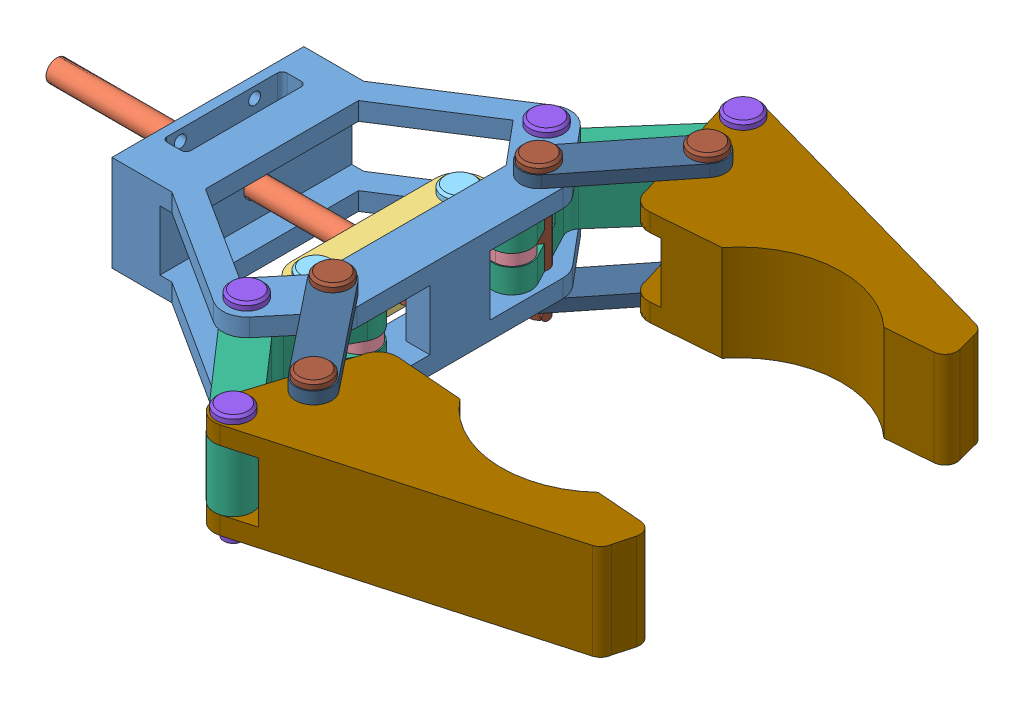
SolidWorks assembly end effactor assem, configuration Default. Lengths in mm.
Overall size (309.65 58.05 248.35).
25 component instances, 11 part files, 58 mates.
Components (placement in the parent):
- part1-2: part1 [Default] at origin size (105.05 40.02 145)
- part10-3: part10 [Default] at (74.5 20 0) x (-1 0 0) z (0 0.889527 -0.456883) size (150 23 23)
- part2-3: part2 [Default] at (62.5 20 0) x (0 0 -1) z (0 -1 0) size (80 20 20)
- part33-1: part33 [Default] at (62.5 20 -30) x (0.995937 0 -0.090048) z (0 -1 0) size (35 15 5)
- part33-2: part33 [Default] at (62.5 20 30) x (0.995937 0 0.090048) z (0 -1 0) size (35 15 5)
- part6-3: part6 [Default] at (62.5 5.25 30) x (1 0 -0.000264) z (0.000264 0 1) size (14 27.8 14)
- part6-4: part6 [Default] at (62.5 5.25 -30) size (14 27.8 14)
- part4-3: part4 [Default] at (66.2 7.5 62.5) x (-0.46713 0 0.884189) z (-0.884189 0 -0.46713) size (71.61 25 70.24)
- part4-4: part4 [Default] at (66.2 32.5 -62.5) x (-0.46713 0 -0.884189) z (-0.884189 0 0.46713) size (71.61 25 70.24)
- part8-3: part8 [Default] at (82.4187 2.5 -31.801) size (14 33.05 14)
- part8-4: part8 [Default] at (82.4187 2.5 31.801) size (14 33.05 14)
- part9-3: part9 [Default] at (104.4001 -5 -106.3078) x (-0.280054 0 -0.959984) z (0.959984 0 -0.280054) size (14 48.05 14)
- part9-4: part9 [Default] at (104.4001 -5 106.3078) x (-0.352892 0 -0.935664) z (0.935664 0 -0.352892) size (14 48.05 14)
- part9-5: part9 [Default] at (66.2 -4.98 -62.5) size (14 48.05 14)
- part9-6: part9 [Default] at (66.2 -4.98 62.5) size (14 48.05 14)
- part5-3: part5 [Default] at (109.3462 20 94.447) x (0.996905 0 0.07861) z (0.07861 0 -0.996905) size (133.83 40 62.87)
- part5-4: part5 [Default] at (109.3462 20 -94.447) x (0.996905 0 -0.07861) z (0.07861 0 0.996905) size (133.83 40 62.87)
- Part3-5: Part3 [Default] at (98.1062 42.52 62.5205) x (0.622248 0 0.78282) z (0 1 0) size (65 15 5)
- Part3-6: Part3 [Default] at (98.1062 -2.5 -62.5205) x (0.622248 0 -0.78282) z (0 -1 0) size (65 15 5)
- Part3-8: Part3 [Default] at (98.1062 42.52 -62.5205) x (0.622248 0 -0.78282) z (0 1 0) size (65 15 5)
- Part3-9: Part3 [Default] at (98.1062 -2.5 62.5205) x (0.622248 0 0.78282) z (0 -1 0) size (65 15 5)
- part7-3: part7 [Default] at (82.55 -9.98 -42.95) x (0.296614 0 -0.954998) z (0.954998 0 0.296614) size (14 58.05 14)
- part7-4: part7 [Default] at (82.55 -9.98 42.95) size (14 58.05 14)
- part7-5: part7 [Default] at (113.6624 -9.98 -82.091) size (14 58.05 14)
- part7-6: part7 [Default] at (113.6624 -9.98 82.091) size (14 58.05 14)
Mates (geometry in assembly coordinates):
- Concentric2: concentric anti-aligned: cylinder of part1-2 through (92.5 20 0) axis (-1 0 0) radius 5; cylinder of part10-3 through (42.8764 20 0) axis (1 0 0) radius 4.5
- LimitDistance1: limit distance = 0 mm anti-aligned: plane of part10-3 through (-9.5 15.9971 2.056) normal (1 0 0); plane of part1-2 through (-9.5 20 0) normal (-1 0 0)
- Concentric4: concentric aligned: cylinder of part10-3 through (42.8764 20 0) axis (1 0 0) radius 4.5; cylinder of part2-3 through (20.8764 20 0) axis (1 0 0) radius 5
- Coincident1: coincident anti-aligned: plane of part10-3 through (38.8764 11.0085 0.3917) normal (-1 0 0); plane of part2-3 through (38.8764 20 0) normal (1 0 0)
- Parallel1: parallel anti-aligned: plane of part2-3 through (30.8764 20 0) normal (0 -1 0); plane of assembly through (0 0 0) normal (0 1 0)
- Concentric5: concentric anti-aligned: cylinder of part2-3 through (30.8764 30 -30) axis (0 -1 0) radius 4; cylinder of part33-1 through (30.8764 17.5 -30) axis (0 1 0) radius 4
- Concentric6: concentric anti-aligned: cylinder of part2-3 through (30.8764 30 30) axis (0 -1 0) radius 4; cylinder of part33-2 through (30.8764 17.5 30) axis (0 1 0) radius 4
- Coincident3: coincident anti-aligned: plane of part2-3 through (20.8764 22.5 -40) normal (0 -1 0); plane of part33-1 through (30.8764 22.5 -30) normal (0 1 0)
- Coincident4: coincident anti-aligned: plane of part2-3 through (20.8764 22.5 40) normal (0 -1 0); plane of part33-2 through (30.8764 22.5 30) normal (0 1 0)
- Concentric7: concentric aligned: cylinder of part2-3 through (30.8764 30 30) axis (0 -1 0) radius 4; cylinder of part6-3 through (30.8764 5.25 30) axis (0 -1 0) radius 4
- Coincident5: coincident anti-aligned: plane of part2-3 through (30.8764 30 30) normal (0 1 0); plane of part6-3 through (30.8764 30 30) normal (0 -1 0)
- Concentric8: concentric aligned: cylinder of part2-3 through (30.8764 30 -30) axis (0 -1 0) radius 4; cylinder of part6-4 through (30.8764 5.25 -30) axis (0 -1 0) radius 4
- Coincident6: coincident anti-aligned: plane of part2-3 through (30.8764 30 30) normal (0 1 0); plane of part6-4 through (30.8764 30 -30) normal (0 -1 0)
- Concentric9: concentric anti-aligned: cylinder of part33-2 through (50.8296 17.5 31.3676) axis (0 1 0) radius 4; cylinder of part4-3 through (50.8296 32.5 31.3676) axis (0 -1 0) radius 4
- Coincident7: coincident anti-aligned: plane of part33-2 through (30.8764 22.5 30) normal (0 1 0); plane of part4-3 through (103.0968 22.5 -3.3593) normal (0 -1 0)
- Concentric10: concentric anti-aligned: cylinder of part1-2 through (66.2 32.52 62.5) axis (0 1 0) radius 4; cylinder of part4-3 through (66.2 32.5 62.5) axis (0 -1 0) radius 4
- Concentric13: concentric aligned: cylinder of part33-1 through (50.8296 17.5 -31.3676) axis (0 1 0) radius 4; cylinder of part4-4 through (50.8296 7.5 -31.3676) axis (0 1 0) radius 4
- Concentric14: concentric aligned: cylinder of part1-2 through (66.2 32.52 -62.5) axis (0 1 0) radius 4; cylinder of part4-4 through (66.2 7.5 -62.5) axis (0 1 0) radius 4
- Coincident8: coincident anti-aligned: plane of part33-1 through (30.8764 22.5 -30) normal (0 1 0); plane of part4-4 through (103.0968 22.5 3.3593) normal (0 -1 0)
- Concentric15: concentric anti-aligned: cylinder of part4-4 through (50.8296 7.5 -31.3676) axis (0 1 0) radius 4; cylinder of part8-3 through (50.8296 2.5 -31.3676) axis (0 -1 0) radius 4
- Concentric16: concentric anti-aligned: cylinder of part4-4 through (50.8296 7.5 -31.3676) axis (0 1 0) radius 4; cylinder of part8-3 through (50.8296 2.5 -31.3676) axis (0 -1 0) radius 4
- Coincident10: coincident anti-aligned: plane of part4-4 through (66.2 32.5 -62.5) normal (0 1 0); plane of part8-3 through (50.8296 32.5 -31.3676) normal (0 -1 0)
- Concentric17: concentric aligned: cylinder of part4-3 through (50.8296 32.5 31.3676) axis (0 -1 0) radius 4; cylinder of part8-4 through (50.8296 2.5 31.3676) axis (0 -1 0) radius 4
- Coincident11: coincident anti-aligned: plane of part4-3 through (66.2 32.5 62.5) normal (0 1 0); plane of part8-4 through (50.8296 32.5 31.3676) normal (0 -1 0)
- Concentric18: concentric anti-aligned: cylinder of part1-2 through (66.2 32.52 62.5) axis (0 1 0) radius 4; cylinder of part9-6 through (66.2 -4.98 62.5) axis (0 -1 0) radius 4
- Concentric19: concentric anti-aligned: cylinder of part1-2 through (66.2 32.52 -62.5) axis (0 1 0) radius 4; cylinder of part9-5 through (66.2 -4.98 -62.5) axis (0 -1 0) radius 4
- Coincident12: coincident anti-aligned: plane of part1-2 through (0 40.02 0) normal (0 1 0); plane of part9-6 through (66.2 40.02 62.5) normal (0 -1 0)
- Coincident13: coincident anti-aligned: plane of part1-2 through (0 40.02 0) normal (0 1 0); plane of part9-5 through (66.2 40.02 -62.5) normal (0 -1 0)
- Concentric21: concentric anti-aligned: cylinder of part4-4 through (124.0834 7.5 -57.2196) axis (0 1 0) radius 4; cylinder of part5-4 through (124.0834 40 -57.2196) axis (0 -1 0) radius 4
- Coincident14: coincident anti-aligned: plane of part4-4 through (66.2 32.5 -62.5) normal (0 1 0); plane of part5-4 through (116.0834 32.5 -65.2196) normal (0 -1 0)
- Concentric22: concentric anti-aligned: cylinder of part4-3 through (124.0834 32.5 57.2196) axis (0 -1 0) radius 4; cylinder of part5-3 through (124.0834 0 57.2196) axis (0 1 0) radius 4
- Coincident15: coincident anti-aligned: plane of part4-3 through (66.2 32.5 62.5) normal (0 1 0); plane of part5-3 through (116.0834 32.5 65.2196) normal (0 -1 0)
- Concentric23: concentric anti-aligned: cylinder of part9-4 through (124.0834 -5 57.2196) axis (0 -1 0) radius 4; cylinder of part5-3 through (124.0834 0 57.2196) axis (0 1 0) radius 4
- Concentric24: concentric aligned: cylinder of part9-3 through (124.0834 -5 -57.2196) axis (0 -1 0) radius 4; cylinder of part5-4 through (124.0834 40 -57.2196) axis (0 -1 0) radius 4
- Coincident16: coincident anti-aligned: plane of part9-3 through (124.0834 40 -57.2196) normal (0 -1 0); plane of part5-4 through (128.0818 40 -45.0066) normal (0 1 0)
- Coincident17: coincident anti-aligned: plane of part9-4 through (124.0834 40 57.2196) normal (0 -1 0); plane of part5-3 through (128.0818 40 45.0066) normal (0 1 0)
- Concentric25: concentric anti-aligned: cylinder of part1-2 through (82.55 32.52 42.95) axis (0 1 0) radius 4; cylinder of Part3-5 through (82.55 45.02 42.95) axis (0 -1 0) radius 4
- Coincident18: coincident anti-aligned: plane of part1-2 through (0 40.02 0) normal (0 1 0); plane of Part3-5 through (82.55 40.02 42.95) normal (0 -1 0)
- Concentric26: concentric anti-aligned: cylinder of part5-3 through (131.4134 0 32.3496) axis (0 1 0) radius 4; cylinder of Part3-5 through (131.4134 45.02 32.3496) axis (0 -1 0) radius 4
- Concentric27: concentric anti-aligned: cylinder of part1-2 through (82.55 32.52 -42.95) axis (0 1 0) radius 4; cylinder of Part3-8 through (82.55 45.02 -42.95) axis (0 -1 0) radius 4
- Coincident19: coincident anti-aligned: plane of part1-2 through (0 40.02 0) normal (0 1 0); plane of Part3-8 through (82.55 40.02 -42.95) normal (0 -1 0)
- Concentric28: concentric aligned: cylinder of part5-4 through (131.4134 40 -32.3496) axis (0 -1 0) radius 4; cylinder of Part3-8 through (131.4134 45.02 -32.3496) axis (0 -1 0) radius 4
- Concentric29: concentric anti-aligned: cylinder of part5-3 through (129.6383 0 59.7634) axis (0 1 0) radius 4; cylinder of ? through (129.6383 -26.8095 59.7634) axis (0 -1 0) radius 4
- Concentric31: concentric anti-aligned: cylinder of part1-2 through (82.55 7.5 42.95) axis (0 -1 0) radius 4; cylinder of Part3-9 through (82.55 -5 42.95) axis (0 1 0) radius 4
- Concentric32: concentric aligned: cylinder of part5-3 through (131.4134 0 32.3496) axis (0 1 0) radius 4; cylinder of Part3-9 through (131.4134 -5 32.3496) axis (0 1 0) radius 4
- Coincident20: coincident anti-aligned: plane of part5-3 through (128.0818 0 45.0066) normal (0 -1 0); plane of Part3-9 through (82.55 0 42.95) normal (0 1 0)
- Concentric33: concentric anti-aligned: cylinder of part1-2 through (82.55 7.5 -42.95) axis (0 -1 0) radius 4; cylinder of Part3-6 through (82.55 -5 -42.95) axis (0 1 0) radius 4
- Concentric35: concentric anti-aligned: cylinder of part5-4 through (131.4134 40 -32.3496) axis (0 -1 0) radius 4; cylinder of Part3-6 through (131.4134 -5 -32.3496) axis (0 1 0) radius 4
- Coincident21: coincident anti-aligned: plane of part5-4 through (128.0818 0 -45.0066) normal (0 -1 0); plane of Part3-6 through (82.55 0 -42.95) normal (0 1 0)
- Concentric36: concentric aligned: cylinder of Part3-8 through (82.55 45.02 -42.95) axis (0 -1 0) radius 4; cylinder of part7-3 through (82.55 -9.98 -42.95) axis (0 -1 0) radius 4
- Concentric37: concentric aligned: cylinder of Part3-5 through (82.55 45.02 42.95) axis (0 -1 0) radius 4; cylinder of part7-4 through (82.55 -9.98 42.95) axis (0 -1 0) radius 4
- Coincident22: coincident anti-aligned: plane of Part3-5 through (82.55 45.02 42.95) normal (0 1 0); plane of part7-4 through (82.55 45.02 42.95) normal (0 -1 0)
- Coincident23: coincident anti-aligned: plane of Part3-8 through (82.55 45.02 -42.95) normal (0 1 0); plane of part7-3 through (82.55 45.02 -42.95) normal (0 -1 0)
- Concentric38: concentric aligned: cylinder of Part3-5 through (131.4134 45.02 32.3496) axis (0 -1 0) radius 4; cylinder of part7-6 through (131.4134 -9.98 32.3496) axis (0 -1 0) radius 4
- Concentric39: concentric aligned: cylinder of Part3-8 through (131.4134 45.02 -32.3496) axis (0 -1 0) radius 4; cylinder of part7-5 through (131.4134 -9.98 -32.3496) axis (0 -1 0) radius 4
- Coincident24: coincident anti-aligned: plane of Part3-8 through (82.55 45.02 -42.95) normal (0 1 0); plane of part7-5 through (131.4134 45.02 -32.3496) normal (0 -1 0)
- Coincident25: coincident anti-aligned: plane of Part3-5 through (82.55 45.02 42.95) normal (0 1 0); plane of part7-6 through (131.4134 45.02 32.3496) normal (0 -1 0)
- LimitAngle1: limit planar angle = 0.157383 rad anti-aligned: plane of part5-4 through (112.6995 40 -51.9219) normal (0.07861 0 0.996905); plane of part5-3 through (112.6995 0 51.9219) normal (0.07861 0 -0.996905)
